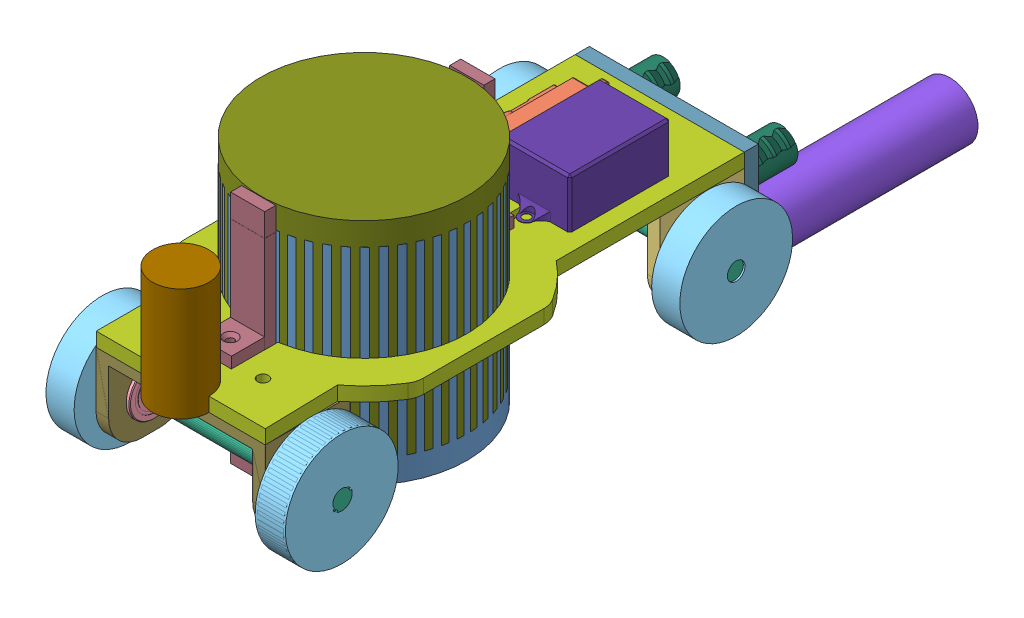
SolidWorks assembly Probe Master, configuration Default. Lengths in mm.
Overall size (108.55 117.87 336.45).
37 component instances, 17 part files, 66 mates.
Components (placement in the parent):
- battery jar v1-1: battery jar v1 [Default] at (59.4741 87.4697 192.7195) x (0.971724 0 0.23612) z (-0.23612 0 0.971724) size (92.96 92.84 92.96) (hidden)
- Servo-1: Servo [預設] at (57.8734 136.9878 87.6912) x (0 0 1) z (0 -1 0) size (54.5 43.19 19.5)
- Wheel Holder-1: Wheel Holder [Default] at (20.8564 86.5995 97.4695) x (-1 0 0) z (0 0 -1) size (76.2 40.01 38.1)
- STAINLESS STEEL BALL BEARING-2: STAINLESS STEEL BALL BEARING [6138K66] at (95.5579 107.7778 78.4195) x (0 -0.802943 -0.596056) z (-1 0 0) size (22.23 22.23 7.14)
- STAINLESS STEEL BALL BEARING-3: STAINLESS STEEL BALL BEARING [6138K66] at (24.9459 107.7778 78.4195) x (0 -0.922928 -0.384973) z (-1 0 0) size (22.23 22.23 7.14)
- Wheel-1: Wheel [Default] at (18.6741 107.7778 78.4195) x (0 0.988152 -0.153476) z (-1 0 0) size (50.8 50.8 12.7)
- STAINLESS STEEL BALL BEARING-4: STAINLESS STEEL BALL BEARING [6138K66] at (94.0022 107.7778 256.2195) x (0 0 -1) z (1 0 0) size (22.23 22.23 7.14) (hidden)
- STAINLESS STEEL BALL BEARING-5: STAINLESS STEEL BALL BEARING [6138K66] at (24.9459 107.7778 256.2195) x (0 0 1) z (-1 0 0) size (22.23 22.23 7.14) (hidden)
- real axel-2: real axel [Default] at (112.9741 107.7778 256.2195) x (0 -0.781777 -0.623558) z (-1 0 0) size (9.53 9.53 107) (hidden)
- Wheel-2: Wheel [Default] at (5.9741 107.7778 256.2195) x (0 0.027995 -0.999608) z (1 0 0) size (50.8 50.8 12.7) (hidden)
- Wheel-3: Wheel [Default] at (100.2741 107.7778 256.2195) x (0 0.063776 -0.997964) z (1 0 0) size (50.8 50.8 12.7)
- Vertical Base-1: Vertical Base [Default] at (51.2333 130.6378 192.9855) size (107.95 6.35 215.9)
- real axel-3: real axel [Default] at (112.9741 107.7778 78.4195) x (0 -0.930183 0.367096) z (-1 0 0) size (9.53 9.53 107) (hidden)
- Wheel-4: Wheel [Default] at (112.9741 107.7778 78.4195) x (0 -0.03437 -0.999409) z (-1 0 0) size (50.8 50.8 12.7)
- Sediment Sample-1: Sediment Sample [Default] at (85.3905 94.8873 -45.4751) x (1 0 0) z (0 -1 0) size (25.4 100 25.4)
- 2in_len_half_in_pvc-1: 2in_len_half_in_pvc [Default] at (59.4741 130.6378 275.2695) size (25.4 50.8 25.4)
- GearServo-2: GearServo [Default] at (55.5578 139.3555 114.3654) x (0 0 1) z (-1 0 0) size (13.63 13.64 3.73)
  - gearServo part1-1: gearServo part1 [Default] at (40.1786 -28.1141 10.1283) size (8.5 8.53 3.23)
  - gearServo part 2-1: gearServo part 2 [Default] at (4.0729 7.3684 9.8743) size (13.59 13.59 0.25)
  - gearServo part 2-2: gearServo part 2 [Default] at (4.0343 7.4237 13.3541) size (13.59 13.59 0.25)
- Wheel Holder_Back-1: Wheel Holder_Back [Default] at (97.997 86.5995 237.1695) size (76.2 40.01 38.1) (hidden)
- CageV3-1: CageV3 [Default] at (51.2808 84.9697 140.8315) x (0 0 1) z (-1 0 0) size (118.8 95.5 34) (hidden)
- springwall-1: springwall [Default] at (21.3741 136.9878 59.3695) x (1 0 0) z (0 0 -1) size (76.2 51.56 6.35)
- spring barb-1: spring barb [Default] at (85.9861 96.4258 53.0195) x (-0.781154 -0.624339 0) z (0.624339 -0.781154 0) size (20.52 21.79 15.18)
- spring barb-2: spring barb [Default] at (85.9861 120.1878 53.0195) x (-0.577939 -0.81608 0) z (0.81608 -0.577939 0) size (20.52 21.79 15.18)
- spring barb-3: spring barb [Default] at (32.9621 96.4258 53.0195) x (-0.781154 -0.624339 0) z (0.624339 -0.781154 0) size (20.52 21.79 15.18)
- spring barb-4: spring barb [Default] at (32.9621 120.1878 53.0195) x (-0.664278 -0.747485 0) z (0.747485 -0.664278 0) size (20.52 21.79 15.18)
- Wheel Holder_Back-2: Wheel Holder_Back [Default] at (98.0917 86.5995 237.1695) size (76.2 40.01 38.1)
- Battery Jar-1: Battery Jar [Default] at (59.4741 97.8466 192.7195) x (0.983461 0 -0.181118) z (0.181118 0 0.983461) size (92.96 92.84 92.96)
- real axel-4: real axel [Default] at (5.202 107.7778 78.4195) x (0 -0.35628 -0.934379) z (1 0 0) size (9.53 9.53 107)
- STAINLESS STEEL BALL BEARING-6: STAINLESS STEEL BALL BEARING [6138K66] at (24.9459 107.7778 256.2195) x (0 0 1) z (-1 0 0) size (22.23 22.23 7.14)
- STAINLESS STEEL BALL BEARING-7: STAINLESS STEEL BALL BEARING [6138K66] at (94.0022 107.7778 256.2195) x (0 -0.258337 -0.966055) z (1 0 0) size (22.23 22.23 7.14)
- Wheel-5: Wheel [Default] at (17.7536 107.7778 256.2195) x (0 -0.862637 0.505823) z (-1 0 0) size (50.8 50.8 12.7)
- Wheel-6: Wheel [Default] at (112.0536 107.7778 256.2195) x (0 -0.070162 0.997536) z (-1 0 0) size (50.8 50.8 12.7)
- real axel-5: real axel [Default] at (5.0536 107.7778 256.2195) x (0 0.102337 -0.99475) z (1 0 0) size (9.53 9.53 107)
- CageV3-3: CageV3 [Default] at (51.2333 95.3878 140.8076) x (0 0 1) z (-1 0 0) size (118.8 95.5 34)
- Part1-2: Part1 [Default] at (57.8734 134.6443 107.5976) x (0 0 1) z (-1 0 0) size (59.1 24.52 32)
Mates (geometry in assembly coordinates):
- Concentric19: concentric aligned: cylinder of Wheel Holder-1 through (130.0861 107.7778 78.4195) axis (-1 0 0) radius 11.176; cylinder of STAINLESS STEEL BALL BEARING-2 through (91.9861 107.7778 78.4195) axis (-1 0 0) radius 11.1125
- Coincident30: coincident aligned: plane of Wheel Holder-1 through (91.9861 90.6278 59.3695) normal (-1 0 0); plane of STAINLESS STEEL BALL BEARING-2 through (91.9861 101.3671 87.0554) normal (-1 0 0)
- Concentric21: concentric anti-aligned: cylinder of Wheel Holder-1 through (-11.1379 107.7778 78.4195) axis (1 0 0) radius 11.176; cylinder of STAINLESS STEEL BALL BEARING-3 through (21.3741 107.7778 78.4195) axis (-1 0 0) radius 11.1125
- Coincident31: coincident aligned: plane of Wheel Holder-1 through (21.3741 130.6378 59.3695) normal (-1 0 0); plane of STAINLESS STEEL BALL BEARING-3 through (21.3741 103.6373 88.3459) normal (-1 0 0)
- Concentric26: concentric anti-aligned: cylinder of STAINLESS STEEL BALL BEARING-5 through (21.3741 107.7778 256.2195) axis (-1 0 0) radius 4.7625; cylinder of real axel-2 through (5.9741 107.7778 256.2195) axis (1 0 0) radius 4.7625
- Concentric27: concentric anti-aligned: cylinder of real axel-2 through (5.9741 107.7778 256.2195) axis (1 0 0) radius 4.7625; cylinder of Wheel-2 through (18.6741 107.7778 256.2195) axis (-1 0 0) radius 4
- Concentric28: concentric anti-aligned: cylinder of real axel-2 through (5.9741 107.7778 256.2195) axis (1 0 0) radius 4.7625; cylinder of Wheel-3 through (112.9741 107.7778 256.2195) axis (-1 0 0) radius 4
- Coincident36: coincident aligned: plane of real axel-2 through (112.9741 107.7778 256.2195) normal (1 0 0); plane of Wheel-3 through (112.9741 107.7778 256.2195) normal (1 0 0)
- Concentric29: concentric aligned: cylinder of battery jar v1-1 through (59.4741 180.3067 192.7195) axis (0 -1 0) radius 46.482; cylinder of Vertical Base-1 through (59.4741 136.9878 192.7195) axis (0 -1 0) radius 46.482
- Coincident38: coincident anti-aligned: plane of Wheel Holder-1 through (97.5741 130.6378 59.3695) normal (0 1 0); plane of Vertical Base-1 through (51.2333 130.6378 192.9855) normal (0 -1 0)
- Concentric30: concentric anti-aligned: cylinder of STAINLESS STEEL BALL BEARING-2 through (91.9861 107.7778 78.4195) axis (-1 0 0) radius 4.7625; cylinder of real axel-3 through (5.9741 107.7778 78.4195) axis (1 0 0) radius 4.7625
- Concentric31: concentric anti-aligned: cylinder of STAINLESS STEEL BALL BEARING-3 through (21.3741 107.7778 78.4195) axis (-1 0 0) radius 4.7625; cylinder of real axel-3 through (5.9741 107.7778 78.4195) axis (1 0 0) radius 4.7625
- Coincident43: coincident aligned: plane of real axel-2 through (5.9741 107.7778 256.2195) normal (-1 0 0); plane of Wheel-2 through (5.9741 107.7778 256.2195) normal (-1 0 0)
- Coincident44: coincident aligned: plane of Wheel-1 through (5.9741 107.7778 78.4195) normal (-1 0 0); plane of real axel-3 through (5.9741 107.7778 78.4195) normal (-1 0 0)
- Concentric32: concentric aligned: cylinder of real axel-3 through (5.9741 107.7778 78.4195) axis (1 0 0) radius 4.7625; cylinder of Wheel-4 through (100.2741 107.7778 78.4195) axis (1 0 0) radius 4
- Coincident45: coincident aligned: plane of real axel-3 through (112.9741 107.7778 78.4195) normal (1 0 0); plane of Wheel-4 through (112.9741 107.7778 78.4195) normal (1 0 0)
- Concentric33: concentric aligned: cylinder of Wheel-1 through (5.9741 107.7778 78.4195) axis (1 0 0) radius 4; cylinder of real axel-3 through (5.9741 107.7778 78.4195) axis (1 0 0) radius 4.7625
- Coincident46: coincident anti-aligned: plane of Servo-1 through (49.3334 136.9878 87.6912) normal (0 -1 0); plane of Vertical Base-1 through (51.2333 136.9878 192.9855) normal (0 1 0)
- Coincident51: coincident anti-aligned: plane of Servo-1 through (49.3334 136.9878 87.6912) normal (0 0 -1); plane of Barquets v2-1 through (63.1184 136.9878 87.6912) normal (0 0 1)
- Coincident52: coincident anti-aligned: plane of Vertical Base-1 through (51.2333 136.9878 192.9855) normal (0 1 0); plane of Barquets v2-1 through (63.1184 136.9878 75.7532) normal (0 -1 0)
- Coincident53: coincident anti-aligned: plane of Servo-1 through (49.3334 136.9878 128.1912) normal (0 0 1); plane of Barquets v2-2 through (77.0884 136.9878 128.1912) normal (0 0 -1)
- Coincident54: coincident anti-aligned: plane of Vertical Base-1 through (51.2333 136.9878 192.9855) normal (0 1 0); plane of Barquets v2-2 through (77.0884 136.9878 140.1292) normal (0 -1 0)
- Parallel1: parallel aligned: plane of Vertical Base-1 through (97.5741 136.9878 192.9855) normal (1 0 0)
- Width1: width anti-aligned: plane of Wheel-1 through (5.9741 107.7778 78.4195) normal (-1 0 0); plane of Wheel-4 through (112.9741 107.7778 78.4195) normal (1 0 0); plane of Wheel Holder-1 through (97.5741 130.6378 59.3695) normal (1 0 0); plane of Wheel Holder-1 through (21.3741 130.6378 59.3695) normal (-1 0 0)
- Coincident56: coincident aligned: plane of Servo-1 through (45.6834 136.9878 87.6912) normal (-1 0 0); plane of Vertical Base-1 through (45.6834 119.4618 133.7156) normal (-1 0 0)
- Width4: width anti-aligned: plane of Barquets v2-1 through (63.1184 139.6061 88.6891) normal (-1 0 0); plane of Barquets v2-1 through (77.0884 139.6061 88.6891) normal (1 0 0); plane of Servo-1 through (84.8734 136.9878 87.6912) normal (1 0 0); plane of Servo-1 through (55.3334 136.9878 87.6912) normal (-1 0 0)
- Width5: width aligned: plane of Barquets v2-2 through (63.1184 139.6061 127.1933) normal (-1 0 0); plane of Barquets v2-2 through (77.0884 139.6061 127.1933) normal (1 0 0); plane of Servo-1 through (55.3334 136.9878 87.6912) normal (-1 0 0); plane of Servo-1 through (84.8734 136.9878 87.6912) normal (1 0 0)
- Concentric37: concentric anti-aligned: cylinder of Vertical Base-1 through (59.4741 126.9878 275.2695) axis (0 1 0) radius 12.7; cylinder of 2in_len_half_in_pvc-1 through (59.4741 181.4378 275.2695) axis (0 -1 0) radius 12.7
- Coincident60: coincident aligned: circle of Vertical Base-1; circle of 2in_len_half_in_pvc-1
- Coincident67: coincident anti-aligned: plane of Servo-1 through (45.6834 136.9878 87.6912) normal (-1 0 0); plane of GearServo-2/gearServo part 2-1 through (45.6834 146.7239 118.4383) normal (1 0 0)
- Concentric49: concentric anti-aligned: cylinder of Servo-1 through (41.6834 146.7378 118.4412) axis (1 0 0) radius 2.925; circle of GearServo-2/gearServo part1-1
- Concentric51: concentric aligned: circle of STAINLESS STEEL BALL BEARING-5; circle of Wheel Holder_Back-1
- Coincident72: coincident anti-aligned: line of Vertical Base-1 through (21.3741 130.6378 275.2695) axis (1 0 0); line of Wheel Holder_Back-1 through (97.4793 130.6378 275.2695) axis (-1 0 0)
- Coincident77: coincident anti-aligned: plane of Vertical Base-1 through (51.2333 115.6518 244.6315) normal (0 0 -1); plane of CageV3-1 through (51.2808 87.4697 244.6315) normal (0 0 1)
- Coincident79: coincident anti-aligned: plane of Vertical Base-1 through (66.6808 115.6518 192.9855) normal (-1 0 0); plane of CageV3-1 through (66.6808 87.4697 140.8315) normal (1 0 0)
- Coincident80: coincident anti-aligned: plane of battery jar v1-1 through (59.4741 87.4697 192.7195) normal (0 -1 0); plane of CageV3-1 through (51.2808 87.4697 140.8315) normal (0 1 0)
- Coincident81: coincident aligned: plane of Wheel Holder-1 through (20.8564 86.5995 59.3695) normal (0 0 -1); plane of Vertical Base-1 through (51.2333 136.9878 59.3695) normal (0 0 -1)
- Coincident82: coincident aligned: plane of Wheel Holder-1 through (97.5741 130.6378 59.3695) normal (1 0 0); plane of Vertical Base-1 through (97.5741 136.9878 192.9855) normal (1 0 0)
- Coincident83: coincident anti-aligned: plane of Wheel Holder-1 through (20.8564 86.5995 59.3695) normal (0 0 -1); plane of springwall-1 through (21.3741 136.9878 59.3695) normal (0 0 1)
- Coincident84: coincident aligned: plane of Vertical Base-1 through (51.2333 136.9878 192.9855) normal (0 1 0); plane of springwall-1 through (21.3741 136.9878 53.0195) normal (0 1 0)
- Coincident85: coincident aligned: plane of Wheel Holder-1 through (21.3741 130.6378 59.3695) normal (-1 0 0); plane of springwall-1 through (21.3741 136.9878 53.0195) normal (-1 0 0)
- Concentric52: concentric aligned: cylinder of springwall-1 through (85.9861 96.4258 85.4355) axis (0 0 -1) radius 2.75; cylinder of spring barb-1 through (85.9861 96.4258 55.9395) axis (0 0 -1) radius 2.5
- Coincident86: coincident anti-aligned: plane of springwall-1 through (21.3741 136.9878 53.0195) normal (0 0 -1); plane of spring barb-1 through (85.9861 96.4258 53.0195) normal (0 0 1)
- Concentric53: concentric anti-aligned: cylinder of springwall-1 through (85.9861 120.1878 -67.6305) axis (0 0 1) radius 2.75; cylinder of spring barb-2 through (85.9861 120.1878 53.0195) axis (0 0 -1) radius 7.5885
- Concentric54: concentric aligned: cylinder of springwall-1 through (32.9621 96.4258 85.4355) axis (0 0 -1) radius 2.75; cylinder of spring barb-3 through (32.9621 96.4258 53.0195) axis (0 0 -1) radius 7.5885
- Concentric55: concentric anti-aligned: cylinder of springwall-1 through (32.9621 120.1878 -67.6305) axis (0 0 1) radius 2.75; cylinder of spring barb-4 through (32.9621 120.1878 53.0195) axis (0 0 -1) radius 7.5885
- Coincident88: coincident anti-aligned: plane of springwall-1 through (21.3741 136.9878 53.0195) normal (0 0 -1); plane of spring barb-4 through (32.9621 120.1878 53.0195) normal (0 0 1)
- Coincident89: coincident anti-aligned: plane of springwall-1 through (21.3741 136.9878 53.0195) normal (0 0 -1); plane of spring barb-3 through (32.9621 96.4258 53.0195) normal (0 0 1)
- Coincident90: coincident anti-aligned: plane of springwall-1 through (21.3741 136.9878 53.0195) normal (0 0 -1); plane of spring barb-2 through (85.9861 120.1878 53.0195) normal (0 0 1)
- Coincident91: coincident anti-aligned: line of Vertical Base-1 through (21.3741 130.6378 275.2695) axis (1 0 0); line of Wheel Holder_Back-2 through (97.5741 130.6378 275.2695) axis (-1 0 0)
- Coincident92: coincident anti-aligned: line of Vertical Base-1 through (21.3741 130.6378 241.3061) axis (0 0 1); line of Wheel Holder_Back-2 through (21.3741 130.6378 275.2695) axis (0 0 -1)
- Concentric56: concentric aligned: cylinder of Vertical Base-1 through (59.4741 136.9878 192.7195) axis (0 -1 0) radius 46.482; cylinder of Battery Jar-1 through (59.4741 190.6836 192.7195) axis (0 -1 0) radius 46.482
- Concentric57: concentric anti-aligned: circle of Wheel-1; circle of real axel-4
- Concentric58: concentric anti-aligned: cylinder of Wheel Holder_Back-2 through (-11.1379 107.7778 256.2195) axis (1 0 0) radius 11.176; cylinder of STAINLESS STEEL BALL BEARING-6 through (21.3741 107.7778 256.2195) axis (-1 0 0) radius 11.1125
- Coincident97: coincident aligned: plane of Wheel Holder_Back-2 through (21.3741 130.6378 275.2695) normal (-1 0 0); plane of STAINLESS STEEL BALL BEARING-6 through (21.3741 118.5331 256.2195) normal (-1 0 0)
- Concentric59: concentric anti-aligned: cylinder of Wheel Holder_Back-2 through (130.0861 107.7778 256.2195) axis (-1 0 0) radius 11.176; cylinder of STAINLESS STEEL BALL BEARING-7 through (97.5741 107.7778 256.2195) axis (1 0 0) radius 11.1125
- Coincident99: coincident aligned: plane of Wheel Holder_Back-2 through (97.5741 130.6378 275.2695) normal (1 0 0); plane of STAINLESS STEEL BALL BEARING-7 through (97.5741 118.168 253.441) normal (1 0 0)
- Concentric60: concentric anti-aligned: cylinder of STAINLESS STEEL BALL BEARING-7 through (97.5741 107.7778 256.2195) axis (1 0 0) radius 4.7625; cylinder of real axel-5 through (112.0536 107.7778 256.2195) axis (-1 0 0) radius 4.7625
- Concentric61: concentric anti-aligned: cylinder of Wheel-6 through (99.3536 107.7778 256.2195) axis (1 0 0) radius 4; cylinder of real axel-5 through (112.0536 107.7778 256.2195) axis (-1 0 0) radius 4.7625
- Concentric62: concentric anti-aligned: cylinder of Wheel-5 through (5.0536 107.7778 256.2195) axis (1 0 0) radius 4; cylinder of real axel-5 through (112.0536 107.7778 256.2195) axis (-1 0 0) radius 4.7625
- Coincident100: coincident aligned: plane of Wheel-5 through (5.0536 107.7778 256.2195) normal (-1 0 0); plane of real axel-5 through (5.0536 107.7778 256.2195) normal (-1 0 0)
- Coincident101: coincident aligned: plane of Wheel-6 through (112.0536 107.7778 256.2195) normal (1 0 0); plane of real axel-5 through (112.0536 107.7778 256.2195) normal (1 0 0)
- Coincident105: coincident anti-aligned: plane of Vertical Base-1 through (51.2333 115.6518 140.8076) normal (0 0 1); plane of CageV3-3 through (51.2333 97.8878 140.8076) normal (0 0 -1)
- Coincident106: coincident anti-aligned: plane of Vertical Base-1 through (51.2333 136.9878 192.9855) normal (0 1 0); plane of CageV3-3 through (51.2333 136.9878 259.6076) normal (0 -1 0)
- Coincident107: coincident anti-aligned: plane of Vertical Base-1 through (51.2333 115.6518 192.9855) normal (1 0 0); plane of CageV3-3 through (51.2333 97.8878 140.8076) normal (-1 0 0)
- Coincident110: coincident anti-aligned: plane of Servo-1 through (84.8734 136.9878 87.6912) normal (1 0 0); plane of Part1-2 through (84.8734 134.6443 107.5976) normal (-1 0 0)
